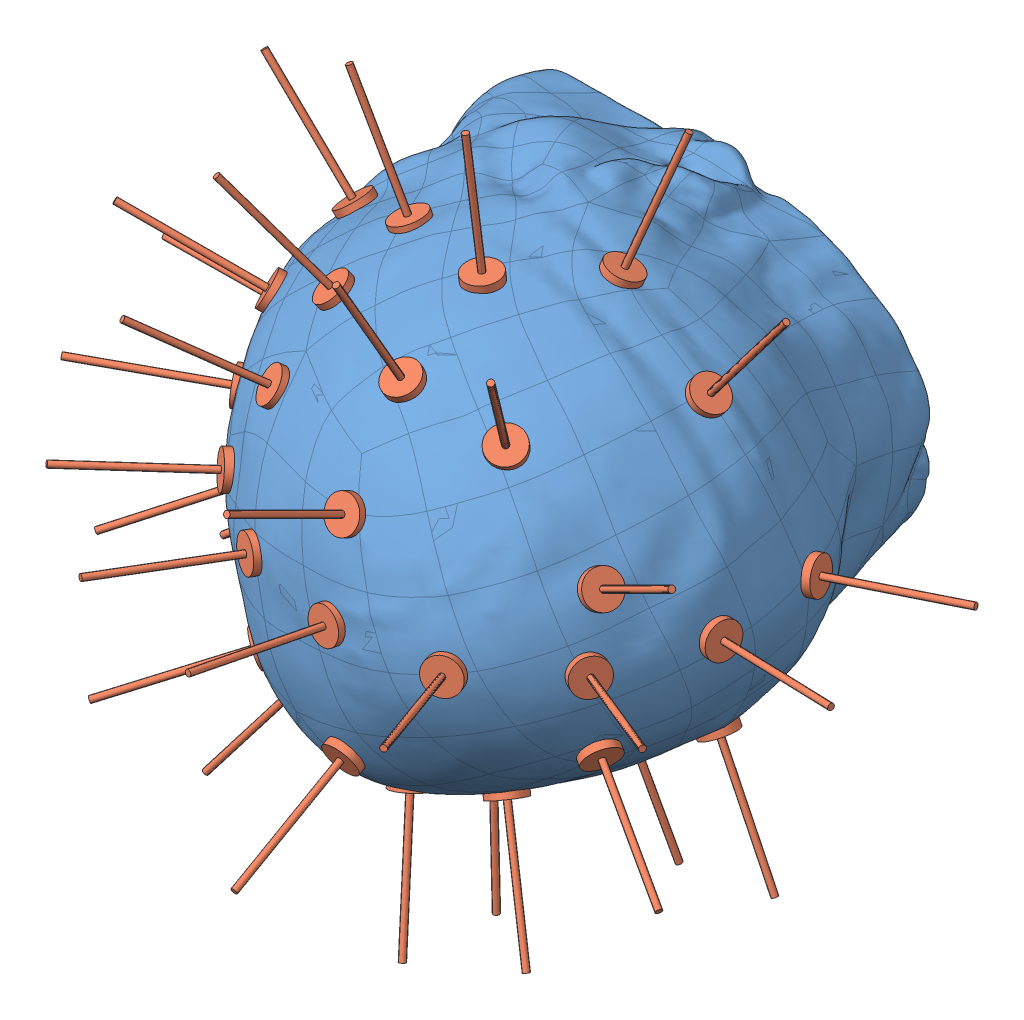
SolidWorks assembly 2_Electrode Positioning, configuration AgCL Elecs. Lengths in mm.
Overall size (190.88 167.77 151.53).
37 component instances, 4 part files, 135 mates.
Components (placement in the parent):
- 1_Creating_Electrode_Positions-1: 1_Creating_Electrode_Positions [Default] at origin
- 0_Electrode_with_clearance -1: 0_Electrode_with_clearance  [AgCL_Small_Elec] at (-101.3217 -81.8741 504.0543) x (0.599277 -0.793127 -0.108704) z (-0.754058 -0.604849 0.256036) size (38 8.5 8.5) (hidden)
- 0_Electrode_with_clearance -2: 0_Electrode_with_clearance  [AgCL_Small_Elec] at (-82.2889 -183.2344 567.2177) x (0.645389 0.335773 -0.686098) z (-0.469655 -0.533934 -0.703093) size (38 8.5 8.5) (hidden)
- 0_Electrode_with_clearance -3: 0_Electrode_with_clearance  [AgCL_Small_Elec] at (-21.5544 -182.7483 591.4589) x (-0.043069 0.440922 -0.896512) z (0.452439 -0.791448 -0.410985) size (38 8.5 8.5) (hidden)
- 0_Electrode_with_clearance -4: 0_Electrode_with_clearance  [AgCL_Small_Elec] at (-79.3288 -210.763 540.8916) x (0.521346 0.779713 -0.346765) z (0.847412 -0.520885 0.10282) size (38 8.5 8.5) (hidden)
- 0_Electrode_with_clearance -5: 0_Electrode_with_clearance  [AgCL_Small_Elec] at (-110.6313 -192.4083 505.1158) x (0.780765 0.610117 -0.134774) z (0.617331 -0.719934 0.317172) size (38 8.5 8.5) (hidden)
- 0_Electrode_with_clearance -6: 0_Electrode_with_clearance  [AgCL_Small_Elec] at (-109.077 -173.871 538.7683) x (0.685975 0.399364 -0.608232) z (0.52825 0.301522 0.793748) size (38 8.5 8.5) (hidden)
- 0_Electrode_with_clearance -7: 0_Electrode_with_clearance  [AgCL_Small_Elec] at (-62.0005 -135.1023 589.8279) x (0.414132 -0.080495 -0.906651) z (-0.0951 -0.994457 0.044852) size (38 8.5 8.5) (hidden)
- 0_Electrode_with_clearance -8: 0_Electrode_with_clearance  [AgCL_Small_Elec] at (-26.2629 -133.863 598.3827) x (0.096504 -0.11805 -0.988307) z (-0.044866 -0.992448 0.114163) size (38 8.5 8.5) (hidden)
- 0_Electrode_with_clearance -9: 0_Electrode_with_clearance  [AgCL_Small_Elec] at (16.3229 -132.4483 591.5644) x (-0.423671 -0.160919 -0.891408) z (0.905732 -0.061861 -0.419312) size (38 8.5 8.5) (hidden)
- 0_Electrode_with_clearance -10: 0_Electrode_with_clearance  [AgCL_Small_Elec] at (-76.3664 -218.9806 512.3458) x (0.403148 0.911153 -0.085279) z (-0.91288 0.393867 -0.107329) size (38 8.5 8.5) (hidden)
- 0_Electrode_with_clearance -11: 0_Electrode_with_clearance  [AgCL_Small_Elec] at (-16.7384 -214.7756 553.7465) x (-0.27015 0.904193 -0.330838) z (0.363231 -0.222513 -0.904738) size (38 8.5 8.5) (hidden)
- 0_Electrode_with_clearance -12: 0_Electrode_with_clearance  [AgCL_Small_Elec] at (9.9013 -206.0821 549.0584) x (-0.44413 0.847467 -0.290773) z (0.27601 -0.179341 -0.944275) size (38 8.5 8.5) (hidden)
- 0_Electrode_with_clearance -13: 0_Electrode_with_clearance  [AgCL_Small_Elec] at (-25.8693 -225.0397 520.8484) x (-0.108878 0.990756 -0.080919) z (0.326961 -0.041181 -0.94414) size (38 8.5 8.5) (hidden)
- 0_Electrode_with_clearance -14: 0_Electrode_with_clearance  [AgCL_Small_Elec] at (-9.153 -220.2716 491.3702) x (-0.275461 0.948005 0.159398) z (0.23104 0.22624 -0.946275) size (38 8.5 8.5) (hidden)
- 0_Electrode_with_clearance -15: 0_Electrode_with_clearance  [AgCL_Small_Elec] at (26.5261 -204.2268 502.863) x (-0.485851 0.873045 -0.041733) z (0.233099 0.083406 -0.96887) size (38 8.5 8.5) (hidden)
- 0_Electrode_with_clearance -16: 0_Electrode_with_clearance  [AgCL_Small_Elec] at (-25.2881 -103.033 589.5857) x (0.02345 -0.436886 -0.899211) z (0.616305 -0.701894 0.35709) size (38 8.5 8.5) (hidden)
- 0_Electrode_with_clearance -17: 0_Electrode_with_clearance  [AgCL_Small_Elec] at (49.4991 -132.0869 559.3095) x (-0.872293 -0.171869 -0.457783) z (0.368185 0.385224 -0.846193) size (38 8.5 8.5) (hidden)
- 0_Electrode_with_clearance -18: 0_Electrode_with_clearance  [AgCL_Small_Elec] at (44.1979 -106.1627 546.607) x (-0.806539 -0.531711 -0.258415) z (-0.500209 0.84676 -0.181078) size (38 8.5 8.5) (hidden)
- 0_Electrode_with_clearance -19: 0_Electrode_with_clearance  [AgCL_Small_Elec] at (45.6239 -173.6394 551.289) x (-0.805041 0.480174 -0.348342) z (0.061106 -0.51696 -0.853826) size (38 8.5 8.5) (hidden)
- 0_Electrode_with_clearance -20: 0_Electrode_with_clearance  [AgCL_Small_Elec] at (61.7604 -134.4581 523.9268) x (-0.986679 -0.100015 -0.1283) z (0.083334 -0.988087 0.129378) size (38 8.5 8.5) (hidden)
- 0_Electrode_with_clearance -21: 0_Electrode_with_clearance  [AgCL_Small_Elec] at (28.3608 -77.9895 501.8243) x (-0.605728 -0.795669 -0.002061) z (0.707034 -0.539436 0.457287) size (38 8.5 8.5) (hidden)
- 0_Electrode_with_clearance -22: 0_Electrode_with_clearance  [AgCL_Small_Elec] at (58.6439 -133.8669 484.1657) x (-0.948505 -0.117932 0.293989) z (0.315365 -0.264534 0.911354) size (38 8.5 8.5) (hidden)
- 0_Electrode_with_clearance -23: 0_Electrode_with_clearance  [AgCL_Small_Elec] at (-10.0826 -62.5213 487.9314) x (-0.251148 -0.931297 0.263838) z (0.611907 0.058442 0.788767) size (38 8.5 8.5) (hidden)
- 0_Electrode_with_clearance -24: 0_Electrode_with_clearance  [AgCL_Small_Elec] at (6.1438 -76.2016 554.3064) x (-0.334952 -0.825131 -0.454935) z (0.746461 -0.527012 0.406268) size (38 8.5 8.5) (hidden)
- 0_Electrode_with_clearance -25: 0_Electrode_with_clearance  [AgCL_Small_Elec] at (-75.1506 -96.9569 566.1233) x (0.501835 -0.539515 -0.676081) z (-0.533614 -0.808268 0.248915) size (38 8.5 8.5) (hidden)
- 0_Electrode_with_clearance -26: 0_Electrode_with_clearance  [AgCL_Small_Elec] at (-33.0522 -57.4526 521.5183) x (0.03497 -0.994627 -0.097441) z (0.11782 -0.092718 0.988697) size (38 8.5 8.5) (hidden)
- 0_Electrode_with_clearance -27: 0_Electrode_with_clearance  [AgCL_Small_Elec] at (-28.7224 -70.1153 558.5267) x (0.027631 -0.870337 -0.491681) z (0.32043 -0.458202 0.829081) size (38 8.5 8.5) (hidden)
- 0_Electrode_with_clearance -28: 0_Electrode_with_clearance  [AgCL_Small_Elec] at (-73.8912 -76.1791 543.5939) x (0.463089 -0.762821 -0.45128) z (0.644267 -0.059941 0.762448) size (38 8.5 8.5) (hidden)
- 0_Electrode_with_clearance -29: 0_Electrode_with_clearance  [AgCL_Small_Elec] at (-71.0435 -65.5829 512.8984) x (0.360614 -0.926276 -0.109405) z (-0.8908 -0.307263 -0.334762) size (38 8.5 8.5) (hidden)
- 0_Electrode_with_clearance -30: 0_Electrode_with_clearance  [AgCL_Small_Elec] at (-128.9888 -138.0006 501.461) x (0.999967 0.007333 -0.00359) z (0.007908 -0.979244 0.202533) size (38 8.5 8.5) (hidden)
- 0_Electrode_with_clearance -31: 0_Electrode_with_clearance  [AgCL_Small_Elec] at (-113.3952 -135.5851 543.1512) x (0.829987 -0.065864 -0.553881) z (-0.514032 0.295195 -0.805376) size (38 8.5 8.5) (hidden)
- 0_Electrode_with_clearance -32: 0_Electrode_with_clearance  [AgCL_Small_Elec] at (-109.5416 -104.4105 533.6089) x (0.764902 -0.453957 -0.456999) z (-0.44793 -0.8847 0.129089) size (38 8.5 8.5) (hidden)
- 0_Electrode_with_clearance -33: 0_Electrode_with_clearance  [AgCL_Small_Elec] at (-89.9639 -133.928 570.4218) x (0.620398 -0.11608 -0.775649) z (-0.284363 -0.954983 -0.084527) size (38 8.5 8.5) (hidden)
- 1_Creating_Electrode_Positions-2: 1_Creating_Electrode_Positions [Default] at origin
- All_Electrodes_Positioned-1: All_Electrodes_Positioned [Default] at origin (suppressed, hidden)
- All_AgCl_Positioned-1: All_AgCl_Positioned [Default] at origin size (190.88 167.77 115.05)
Mates (geometry in assembly coordinates):
- Concentric1: concentric anti-aligned: line of 1_Creating_Electrode_Positions-1 through (-81.5455 -108.0473 500.467) axis (-0.599277 0.793127 0.108704); cylinder of 0_Electrode_with_clearance -1 through (-81.5455 -108.0473 500.467) axis (0.599277 -0.793127 -0.108704) radius 2.1
- Distance1: distance = 5 mm: plane of 0_Electrode_with_clearance -1 through (-78.5491 -112.0129 499.9235) normal (0.599277 -0.793127 -0.108704); point of 1_Creating_Electrode_Positions-1
- Concentric2: concentric anti-aligned: line of 1_Creating_Electrode_Positions-1 through (-86.4398 -160.692 518.6967) axis (-0.685975 -0.399364 0.608232); cylinder of 0_Electrode_with_clearance -6 through (-86.4398 -160.692 518.6967) axis (0.685975 0.399364 -0.608232) radius 2.1
- Distance2: distance = 5 mm: plane of 0_Electrode_with_clearance -6 through (-83.0099 -158.6952 515.6555) normal (0.685975 0.399364 -0.608232); point of 1_Creating_Electrode_Positions-1
- Concentric3: concentric anti-aligned: line of 1_Creating_Electrode_Positions-1 through (-84.8661 -172.2744 500.6683) axis (-0.780765 -0.610117 0.134774); cylinder of 0_Electrode_with_clearance -5 through (-84.8661 -172.2744 500.6683) axis (0.780765 0.610117 -0.134774) radius 2.1
- Distance3: distance = 5 mm: plane of 0_Electrode_with_clearance -5 through (-80.9623 -169.2238 499.9944) normal (0.780765 0.610117 -0.134774); point of 1_Creating_Electrode_Positions-1
- Concentric5: concentric anti-aligned: line of 1_Creating_Electrode_Positions-1 through (-58.0591 -178.9526 526.7445) axis (-0.521346 -0.779713 0.346765); cylinder of 0_Electrode_with_clearance -4 through (-62.1243 -185.0325 529.4484) axis (0.521346 0.779713 -0.346765) radius 2.1
- Distance4: distance = 5 mm: plane of 0_Electrode_with_clearance -4 through (-59.5176 -181.134 527.7146) normal (0.521346 0.779713 -0.346765); point of 1_Creating_Electrode_Positions-1
- Concentric8: concentric anti-aligned: line of 1_Creating_Electrode_Positions-1 through (-60.9911 -172.1539 544.5765) axis (-0.645389 -0.335773 0.686098); cylinder of 0_Electrode_with_clearance -2 through (-60.9911 -172.1539 544.5765) axis (0.645389 0.335773 -0.686098) radius 2.1
- Distance5: distance = 5 mm: plane of 0_Electrode_with_clearance -2 through (-57.7642 -170.4751 541.146) normal (0.645389 0.335773 -0.686098); point of 1_Creating_Electrode_Positions-1
- Concentric9: concentric anti-aligned: line of 1_Creating_Electrode_Positions-1 through (-22.9757 -168.1979 561.874) axis (0.043069 -0.440922 0.896512); cylinder of 0_Electrode_with_clearance -3 through (-22.9757 -168.1979 561.874) axis (-0.043069 0.440922 -0.896512) radius 2.1
- Distance6: distance = 5 mm: point of 1_Creating_Electrode_Positions-1; plane of 0_Electrode_with_clearance -3 through (-23.191 -165.9933 557.3915) normal (-0.043069 0.440922 -0.896512)
- Concentric10: concentric anti-aligned: line of 1_Creating_Electrode_Positions-1 through (-48.3342 -137.7586 559.9084) axis (-0.414132 0.080495 0.906651); cylinder of 0_Electrode_with_clearance -7 through (-48.3342 -137.7586 559.9084) axis (0.414132 -0.080495 -0.906651) radius 2.1
- Distance7: distance = 5 mm: plane of 0_Electrode_with_clearance -7 through (-46.2635 -138.1611 555.3751) normal (0.414132 -0.080495 -0.906651); point of 1_Creating_Electrode_Positions-1
- Concentric11: concentric anti-aligned: line of 1_Creating_Electrode_Positions-1 through (-23.0782 -137.7586 565.7686) axis (-0.096504 0.11805 0.988307); cylinder of 0_Electrode_with_clearance -8 through (-23.0782 -137.7586 565.7686) axis (0.096504 -0.11805 -0.988307) radius 2.1
- Distance8: distance = 5 mm: plane of 0_Electrode_with_clearance -8 through (-22.5957 -138.3489 560.827) normal (0.096504 -0.11805 -0.988307); point of 1_Creating_Electrode_Positions-1
- Concentric12: concentric anti-aligned: line of 1_Creating_Electrode_Positions-1 through (-1.7771 -139.323 553.4819) axis (0.423671 0.160919 0.891408); cylinder of 0_Electrode_with_clearance -9 through (2.3417 -137.7586 562.148) axis (-0.423671 -0.160919 -0.891408) radius 2.1
- Distance9: distance = 5 mm: plane of 0_Electrode_with_clearance -9 through (0.2234 -138.5632 557.6909) normal (-0.423671 -0.160919 -0.891408); point of 1_Creating_Electrode_Positions-1
- Concentric13: concentric anti-aligned: line of 1_Creating_Electrode_Positions-1 through (-59.4862 -180.8298 508.7751) axis (-0.403148 -0.911153 0.085279); cylinder of 0_Electrode_with_clearance -10 through (-63.0625 -188.9125 509.5316) axis (0.403148 0.911153 -0.085279) radius 2.1
- Distance10: distance = 5 mm: point of 1_Creating_Electrode_Positions-1; plane of 0_Electrode_with_clearance -10 through (-61.0468 -184.3568 509.1052) normal (0.403148 0.911153 -0.085279)
- Concentric14: concentric anti-aligned: line of 1_Creating_Electrode_Positions-1 through (-28.1573 -176.5567 539.7624) axis (0.27015 -0.904193 0.330838); cylinder of 0_Electrode_with_clearance -11 through (-25.6534 -184.9372 542.8288) axis (-0.27015 0.904193 -0.330838) radius 2.1
- Distance11: distance = 5 mm: point of 1_Creating_Electrode_Positions-1; plane of 0_Electrode_with_clearance -11 through (-27.0041 -180.4163 541.1746) normal (-0.27015 0.904193 -0.330838)
- Concentric15: concentric anti-aligned: line of 1_Creating_Electrode_Positions-1 through (-4.755 -178.1157 539.4629) axis (0.44413 -0.847467 0.290773); cylinder of 0_Electrode_with_clearance -12 through (-4.755 -178.1157 539.4629) axis (-0.44413 0.847467 -0.290773) radius 2.1
- Distance12: distance = 5 mm: point of 1_Creating_Electrode_Positions-1; plane of 0_Electrode_with_clearance -12 through (-6.9757 -173.8784 538.0091) normal (-0.44413 0.847467 -0.290773)
- Concentric16: concentric anti-aligned: line of 1_Creating_Electrode_Positions-1 through (-29.4623 -192.3447 518.1781) axis (0.108878 -0.990756 0.080919); cylinder of 0_Electrode_with_clearance -13 through (-29.4623 -192.3447 518.1781) axis (-0.108878 0.990756 -0.080919) radius 2.1
- Distance13: distance = 5 mm: point of 1_Creating_Electrode_Positions-1; plane of 0_Electrode_with_clearance -13 through (-30.0067 -187.3909 517.7735) normal (-0.108878 0.990756 -0.080919)
- Concentric17: concentric anti-aligned: line of 1_Creating_Electrode_Positions-1 through (-20.4193 -181.4984 497.8895) axis (0.275461 -0.948005 -0.159398); cylinder of 0_Electrode_with_clearance -14 through (-18.2432 -188.9874 496.6303) axis (-0.275461 0.948005 0.159398) radius 2.1
- Distance14: distance = 5 mm: point of 1_Creating_Electrode_Positions-1; plane of 0_Electrode_with_clearance -14 through (-19.6205 -184.2474 497.4273) normal (-0.275461 0.948005 0.159398)
- Concentric18: concentric anti-aligned: line of 1_Creating_Electrode_Positions-1 through (10.4931 -175.4164 501.4858) axis (0.485851 -0.873045 0.041733); cylinder of 0_Electrode_with_clearance -15 through (10.4931 -175.4164 501.4858) axis (-0.485851 0.873045 -0.041733) radius 2.1
- Distance15: distance = 5 mm: point of 1_Creating_Electrode_Positions-1; plane of 0_Electrode_with_clearance -15 through (8.0638 -171.0511 501.2771) normal (-0.485851 0.873045 -0.041733)
- Concentric19: concentric anti-aligned: line of 1_Creating_Electrode_Positions-1 through (14.1338 -154.8568 537.6632) axis (0.805041 -0.480174 0.348342); cylinder of 0_Electrode_with_clearance -19 through (19.0575 -157.7936 539.7937) axis (-0.805041 0.480174 -0.348342) radius 2.1
- Distance16: distance = 5 mm: point of 1_Creating_Electrode_Positions-1; plane of 0_Electrode_with_clearance -19 through (15.0323 -155.3928 538.052) normal (-0.805041 0.480174 -0.348342)
- Concentric20: concentric anti-aligned: line of 1_Creating_Electrode_Positions-1 through (20.7135 -137.7586 544.2026) axis (0.872293 0.171869 0.457783); cylinder of 0_Electrode_with_clearance -17 through (20.7135 -137.7586 544.2026) axis (-0.872293 -0.171869 -0.457783) radius 2.1
- Distance17: distance = 5 mm: plane of 0_Electrode_with_clearance -17 through (16.352 -138.618 541.9137) normal (-0.872293 -0.171869 -0.457783); point of 1_Creating_Electrode_Positions-1
- Concentric21: concentric anti-aligned: line of 1_Creating_Electrode_Positions-1 through (-24.5142 -117.4502 559.9117) axis (-0.02345 0.436886 0.899211); cylinder of 0_Electrode_with_clearance -16 through (-24.5142 -117.4502 559.9117) axis (0.02345 -0.436886 -0.899211) radius 2.1
- Distance18: distance = 5 mm: point of 1_Creating_Electrode_Positions-1; plane of 0_Electrode_with_clearance -16 through (-24.397 -119.6346 555.4157) normal (0.02345 -0.436886 -0.899211)
- Concentric23: concentric anti-aligned: line of 1_Creating_Electrode_Positions-1 through (10.7527 -128.2114 535.8912) axis (0.806539 0.531711 0.258415); cylinder of 0_Electrode_with_clearance -18 through (17.5821 -123.7092 538.0793) axis (-0.806539 -0.531711 -0.258415) radius 2.1
- Distance19: distance = 5 mm: point of 1_Creating_Electrode_Positions-1; plane of 0_Electrode_with_clearance -18 through (13.5494 -126.3677 536.7872) normal (-0.806539 -0.531711 -0.258415)
- Concentric24: concentric anti-aligned: line of 1_Creating_Electrode_Positions-1 through (20.8846 -138.6015 518.6116) axis (0.986679 0.100015 0.1283); cylinder of 0_Electrode_with_clearance -20 through (29.2 -137.7586 519.6929) axis (-0.986679 -0.100015 -0.1283) radius 2.1
- Distance20: distance = 5 mm: plane of 0_Electrode_with_clearance -20 through (24.2666 -138.2587 519.0514) normal (-0.986679 -0.100015 -0.1283); point of 1_Creating_Electrode_Positions-1
- Concentric25: concentric anti-aligned: line of 1_Creating_Electrode_Positions-1 through (8.3718 -104.2466 501.7563) axis (0.605728 0.795669 0.002061); cylinder of 0_Electrode_with_clearance -21 through (8.3718 -104.2466 501.7563) axis (-0.605728 -0.795669 -0.002061) radius 2.1
- Distance21: distance = 5 mm: point of 1_Creating_Electrode_Positions-1; plane of 0_Electrode_with_clearance -21
- Concentric26: concentric anti-aligned: line of 1_Creating_Electrode_Positions-1 through (27.3432 -137.7586 493.8674) axis (0.948505 0.117932 -0.293989); cylinder of 0_Electrode_with_clearance -22 through (27.3432 -137.7586 493.8674) axis (-0.948505 -0.117932 0.293989) radius 2.1
- Distance22: distance = 5 mm: plane of 0_Electrode_with_clearance -22 through (22.6007 -138.3483 495.3373) normal (-0.948505 -0.117932 0.293989); point of 1_Creating_Electrode_Positions-1
- Concentric27: concentric anti-aligned: line of 1_Creating_Electrode_Positions-1 through (-18.3704 -93.2541 496.638) axis (0.251148 0.931297 -0.263838); cylinder of 0_Electrode_with_clearance -23 through (-18.3704 -93.2541 496.638) axis (-0.251148 -0.931297 0.263838) radius 2.1
- Distance23: distance = 5 mm: plane of 0_Electrode_with_clearance -23 through (-19.6262 -97.9106 497.9572) normal (-0.251148 -0.931297 0.263838); point of 1_Creating_Electrode_Positions-1
- Concentric28: concentric anti-aligned: line of 1_Creating_Electrode_Positions-1 through (-4.9096 -103.431 539.2935) axis (0.334952 0.825131 0.454935); cylinder of 0_Electrode_with_clearance -24 through (-4.9096 -103.431 539.2935) axis (-0.334952 -0.825131 -0.454935) radius 2.1
- Distance24: distance = 5 mm: point of 1_Creating_Electrode_Positions-1; plane of 0_Electrode_with_clearance -24 through (-6.5844 -107.5566 537.0189) normal (-0.334952 -0.825131 -0.454935)
- Concentric29: concentric anti-aligned: line of 1_Creating_Electrode_Positions-1 through (-27.5526 -106.9607 537.7116) axis (-0.027631 0.870337 0.491681); cylinder of 0_Electrode_with_clearance -27 through (-27.8105 -98.8364 542.3012) axis (0.027631 -0.870337 -0.491681) radius 2.1
- Distance25: distance = 5 mm: point of 1_Creating_Electrode_Positions-1; plane of 0_Electrode_with_clearance -27 through (-27.6724 -103.1881 539.8428) normal (0.027631 -0.870337 -0.491681)
- Concentric30: concentric anti-aligned: line of 1_Creating_Electrode_Positions-1 through (-53.6573 -120.064 537.1671) axis (-0.501835 0.539515 0.676081); cylinder of 0_Electrode_with_clearance -25 through (-58.5901 -114.7609 543.8127) axis (0.501835 -0.539515 -0.676081) radius 2.1
- Distance26: distance = 5 mm: plane of 0_Electrode_with_clearance -25 through (-56.0809 -117.4585 540.4322) normal (0.501835 -0.539515 -0.676081); point of 1_Creating_Electrode_Positions-1
- Concentric32: concentric anti-aligned: line of 1_Creating_Electrode_Positions-1 through (-59.1432 -96.1501 509.288) axis (-0.360614 0.926276 0.109405); cylinder of 0_Electrode_with_clearance -29 through (-59.1432 -96.1501 509.288) axis (0.360614 -0.926276 -0.109405) radius 2.1
- Distance27: distance = 5 mm: plane of 0_Electrode_with_clearance -29 through (-57.3402 -100.7814 508.741) normal (0.360614 -0.926276 -0.109405); point of 1_Creating_Electrode_Positions-1
- Concentric33: concentric anti-aligned: line of 1_Creating_Electrode_Positions-1 through (-58.6093 -101.3522 528.7016) axis (-0.463089 0.762821 0.45128); cylinder of 0_Electrode_with_clearance -28 through (-58.6093 -101.3522 528.7016) axis (0.463089 -0.762821 -0.45128) radius 2.1
- Distance28: distance = 5 mm: point of 1_Creating_Electrode_Positions-1; plane of 0_Electrode_with_clearance -28 through (-56.2938 -105.1663 526.4452) normal (0.463089 -0.762821 -0.45128)
- Concentric34: concentric anti-aligned: line of 1_Creating_Electrode_Positions-1 through (-31.8982 -90.2753 518.3028) axis (-0.03497 0.994627 0.097441); cylinder of 0_Electrode_with_clearance -26 through (-31.8982 -90.2753 518.3028) axis (0.03497 -0.994627 -0.097441) radius 2.1
- Distance29: distance = 5 mm: point of 1_Creating_Electrode_Positions-1; plane of 0_Electrode_with_clearance -26 through (-31.7233 -95.2484 517.8155) normal (0.03497 -0.994627 -0.097441)
- Concentric35: concentric anti-aligned: line of 1_Creating_Electrode_Positions-1 through (-95.9899 -137.7586 501.3425) axis (-0.999967 -0.007333 0.00359); cylinder of 0_Electrode_with_clearance -30 through (-95.9899 -137.7586 501.3425) axis (0.999967 0.007333 -0.00359) radius 2.1
- Distance30: distance = 5 mm: point of 1_Creating_Electrode_Positions-1; plane of 0_Electrode_with_clearance -30 through (-90.9901 -137.722 501.3245) normal (0.999967 0.007333 -0.00359)
- Concentric36: concentric anti-aligned: line of 1_Creating_Electrode_Positions-1 through (-86.0056 -137.7586 524.8731) axis (-0.829987 0.065864 0.553881); cylinder of 0_Electrode_with_clearance -31 through (-86.0056 -137.7586 524.8731) axis (0.829987 -0.065864 -0.553881) radius 2.1
- Distance31: distance = 5 mm: point of 1_Creating_Electrode_Positions-1; plane of 0_Electrode_with_clearance -31 through (-81.8557 -138.088 522.1037) normal (0.829987 -0.065864 -0.553881)
- Concentric37: concentric anti-aligned: line of 1_Creating_Electrode_Positions-1 through (-84.2998 -119.3911 518.528) axis (-0.764902 0.453957 0.456999); cylinder of 0_Electrode_with_clearance -32 through (-84.2998 -119.3911 518.528) axis (0.764902 -0.453957 -0.456999) radius 2.1
- Distance32: distance = 5 mm: point of 1_Creating_Electrode_Positions-1; plane of 0_Electrode_with_clearance -32 through (-80.4753 -121.6609 516.243) normal (0.764902 -0.453957 -0.456999)
- Concentric38: concentric anti-aligned: line of 1_Creating_Electrode_Positions-1 through (-69.4908 -137.7586 544.8254) axis (-0.620398 0.11608 0.775649); cylinder of 0_Electrode_with_clearance -33 through (-69.4908 -137.7586 544.8254) axis (0.620398 -0.11608 -0.775649) radius 2.1
- Distance33: distance = 5 mm: point of 1_Creating_Electrode_Positions-1; plane of 0_Electrode_with_clearance -33 through (-66.3888 -138.339 540.9471) normal (0.620398 -0.11608 -0.775649)
- Coincident40: coincident aligned: plane of 1_Creating_Electrode_Positions-1; plane of 1_Creating_Electrode_Positions-2
- Coincident41: coincident aligned: plane of 1_Creating_Electrode_Positions-1 through (0 0 0) normal (0 1 0); plane of 1_Creating_Electrode_Positions-2 through (0 0 0) normal (0 1 0)
- Coincident42: coincident aligned: plane of 1_Creating_Electrode_Positions-1 through (0 0 0) normal (1 0 0); plane of 1_Creating_Electrode_Positions-2 through (0 0 0) normal (1 0 0)
- Coincident43: coincident anti-aligned: line of 1_Creating_Electrode_Positions-1 through (-60.9911 -172.1539 544.5765) axis (-0.645389 -0.335773 0.686098); line of 0_Electrode_with_clearance -2 through (-82.2889 -183.2344 567.2177) axis (0.645389 0.335773 -0.686098)
- Coincident44: coincident: point of 1_Creating_Electrode_Positions-1; point of 0_Electrode_with_clearance -2
- Coincident45: coincident anti-aligned: line of 1_Creating_Electrode_Positions-1 through (-81.5455 -108.0473 500.467) axis (-0.599277 0.793127 0.108704); line of 0_Electrode_with_clearance -1 through (-101.3217 -81.8741 504.0543) axis (0.599277 -0.793127 -0.108704)
- Coincident46: coincident: point of 1_Creating_Electrode_Positions-1; point of 0_Electrode_with_clearance -1
- Coincident47: coincident anti-aligned: line of 1_Creating_Electrode_Positions-1 through (-22.9757 -168.1979 561.874) axis (0.043069 -0.440922 0.896512); line of 0_Electrode_with_clearance -3 through (-21.5544 -182.7483 591.4589) axis (-0.043069 0.440922 -0.896512)
- Coincident48: coincident: point of 1_Creating_Electrode_Positions-1; point of 0_Electrode_with_clearance -3
- Coincident49: coincident anti-aligned: line of 1_Creating_Electrode_Positions-1 through (-58.0591 -178.9526 526.7445) axis (-0.521346 -0.779713 0.346765); line of 0_Electrode_with_clearance -4 through (-79.3288 -210.763 540.8916) axis (0.521346 0.779713 -0.346765)
- Coincident50: coincident: point of 1_Creating_Electrode_Positions-1; point of 0_Electrode_with_clearance -4
- Coincident51: coincident anti-aligned: line of 1_Creating_Electrode_Positions-1 through (-84.8661 -172.2744 500.6683) axis (-0.780765 -0.610117 0.134774); line of 0_Electrode_with_clearance -5 through (-110.6313 -192.4083 505.1158) axis (0.780765 0.610117 -0.134774)
- Coincident52: coincident: point of 1_Creating_Electrode_Positions-1; point of 0_Electrode_with_clearance -5
- Coincident53: coincident anti-aligned: line of 1_Creating_Electrode_Positions-1 through (-86.4398 -160.692 518.6967) axis (-0.685975 -0.399364 0.608232); line of 0_Electrode_with_clearance -6 through (-109.077 -173.871 538.7683) axis (0.685975 0.399364 -0.608232)
- Coincident54: coincident: point of 1_Creating_Electrode_Positions-1; point of 0_Electrode_with_clearance -6
- Coincident55: coincident anti-aligned: line of 1_Creating_Electrode_Positions-1 through (-48.3342 -137.7586 559.9084) axis (-0.414132 0.080495 0.906651); line of 0_Electrode_with_clearance -7 through (-62.0005 -135.1023 589.8279) axis (0.414132 -0.080495 -0.906651)
- Coincident56: coincident: point of 1_Creating_Electrode_Positions-1; point of 0_Electrode_with_clearance -7
- Coincident57: coincident anti-aligned: line of 1_Creating_Electrode_Positions-1 through (-23.0782 -137.7586 565.7686) axis (-0.096504 0.11805 0.988307); line of 0_Electrode_with_clearance -8 through (-26.2629 -133.863 598.3827) axis (0.096504 -0.11805 -0.988307)
- Coincident58: coincident: point of 1_Creating_Electrode_Positions-1; point of 0_Electrode_with_clearance -8
- Coincident59: coincident anti-aligned: line of 1_Creating_Electrode_Positions-1 through (-1.7771 -139.323 553.4819) axis (0.423671 0.160919 0.891408); line of 0_Electrode_with_clearance -9 through (16.3229 -132.4483 591.5644) axis (-0.423671 -0.160919 -0.891408)
- Coincident60: coincident: point of 1_Creating_Electrode_Positions-1; point of 0_Electrode_with_clearance -9
- Coincident61: coincident anti-aligned: line of 1_Creating_Electrode_Positions-1 through (-59.4862 -180.8298 508.7751) axis (-0.403148 -0.911153 0.085279); line of 0_Electrode_with_clearance -10 through (-76.3664 -218.9806 512.3458) axis (0.403148 0.911153 -0.085279)
- Coincident62: coincident: point of 1_Creating_Electrode_Positions-1; point of 0_Electrode_with_clearance -10
- Coincident63: coincident anti-aligned: line of 1_Creating_Electrode_Positions-1 through (-28.1573 -176.5567 539.7624) axis (0.27015 -0.904193 0.330838); line of 0_Electrode_with_clearance -11 through (-16.7384 -214.7756 553.7465) axis (-0.27015 0.904193 -0.330838)
- Coincident64: coincident: point of 1_Creating_Electrode_Positions-1; point of 0_Electrode_with_clearance -11
- Coincident65: coincident anti-aligned: line of 1_Creating_Electrode_Positions-1 through (-4.755 -178.1157 539.4629) axis (0.44413 -0.847467 0.290773); line of 0_Electrode_with_clearance -12 through (9.9013 -206.0821 549.0584) axis (-0.44413 0.847467 -0.290773)
- Coincident66: coincident: point of 1_Creating_Electrode_Positions-1; point of 0_Electrode_with_clearance -12
- Coincident67: coincident anti-aligned: line of 1_Creating_Electrode_Positions-1 through (-29.4623 -192.3447 518.1781) axis (0.108878 -0.990756 0.080919); line of 0_Electrode_with_clearance -13 through (-25.8693 -225.0397 520.8484) axis (-0.108878 0.990756 -0.080919)
- Coincident68: coincident: point of 1_Creating_Electrode_Positions-1; point of 0_Electrode_with_clearance -13
- Coincident69: coincident anti-aligned: line of 1_Creating_Electrode_Positions-1 through (-20.4193 -181.4984 497.8895) axis (0.275461 -0.948005 -0.159398); line of 0_Electrode_with_clearance -14 through (-9.153 -220.2716 491.3702) axis (-0.275461 0.948005 0.159398)
- Coincident70: coincident: point of 1_Creating_Electrode_Positions-1; point of 0_Electrode_with_clearance -14
- Coincident71: coincident anti-aligned: line of 1_Creating_Electrode_Positions-1 through (10.4931 -175.4164 501.4858) axis (0.485851 -0.873045 0.041733); line of 0_Electrode_with_clearance -15 through (26.5261 -204.2268 502.863) axis (-0.485851 0.873045 -0.041733)
- Coincident72: coincident: point of 1_Creating_Electrode_Positions-1; point of 0_Electrode_with_clearance -15
- Coincident73: coincident anti-aligned: line of 1_Creating_Electrode_Positions-1 through (-24.5142 -117.4502 559.9117) axis (-0.02345 0.436886 0.899211); line of 0_Electrode_with_clearance -16 through (-25.2881 -103.033 589.5857) axis (0.02345 -0.436886 -0.899211)
- Coincident74: coincident: point of 1_Creating_Electrode_Positions-1; point of 0_Electrode_with_clearance -16
- Coincident75: coincident anti-aligned: line of 1_Creating_Electrode_Positions-1 through (20.7135 -137.7586 544.2026) axis (0.872293 0.171869 0.457783); line of 0_Electrode_with_clearance -17 through (49.4991 -132.0869 559.3095) axis (-0.872293 -0.171869 -0.457783)
- Coincident76: coincident: point of 1_Creating_Electrode_Positions-1; point of 0_Electrode_with_clearance -17
- Coincident77: coincident: point of 1_Creating_Electrode_Positions-1; point of 0_Electrode_with_clearance -18
- Coincident78: coincident anti-aligned: line of 1_Creating_Electrode_Positions-1 through (10.7527 -128.2114 535.8912) axis (0.806539 0.531711 0.258415); line of 0_Electrode_with_clearance -18 through (44.1979 -106.1627 546.607) axis (-0.806539 -0.531711 -0.258415)
- Coincident79: coincident anti-aligned: line of 1_Creating_Electrode_Positions-1 through (14.1338 -154.8568 537.6632) axis (0.805041 -0.480174 0.348342); line of 0_Electrode_with_clearance -19 through (45.6239 -173.6394 551.289) axis (-0.805041 0.480174 -0.348342)
- Coincident80: coincident: point of 0_Electrode_with_clearance -19; point of 1_Creating_Electrode_Positions-1
- Coincident81: coincident anti-aligned: line of 1_Creating_Electrode_Positions-1 through (20.8846 -138.6015 518.6116) axis (0.986679 0.100015 0.1283); line of 0_Electrode_with_clearance -20 through (61.7604 -134.4581 523.9268) axis (-0.986679 -0.100015 -0.1283)
- Coincident82: coincident: point of 1_Creating_Electrode_Positions-1; point of 0_Electrode_with_clearance -20
- Coincident83: coincident: point of 0_Electrode_with_clearance -21; point of 1_Creating_Electrode_Positions-1
- Coincident84: coincident anti-aligned: line of 1_Creating_Electrode_Positions-1 through (8.3718 -104.2466 501.7563) axis (0.605728 0.795669 0.002061); line of 0_Electrode_with_clearance -21 through (28.3608 -77.9895 501.8243) axis (-0.605728 -0.795669 -0.002061)
- Coincident85: coincident: point of 1_Creating_Electrode_Positions-1; point of 0_Electrode_with_clearance -22
- Coincident86: coincident anti-aligned: line of 1_Creating_Electrode_Positions-1 through (27.3432 -137.7586 493.8674) axis (0.948505 0.117932 -0.293989); line of 0_Electrode_with_clearance -22 through (58.6439 -133.8669 484.1657) axis (-0.948505 -0.117932 0.293989)
- Coincident87: coincident: point of 1_Creating_Electrode_Positions-1; point of 0_Electrode_with_clearance -23
- Coincident88: coincident anti-aligned: line of 1_Creating_Electrode_Positions-1 through (-18.3704 -93.2541 496.638) axis (0.251148 0.931297 -0.263838); line of 0_Electrode_with_clearance -23 through (-10.0826 -62.5213 487.9314) axis (-0.251148 -0.931297 0.263838)
- Coincident89: coincident anti-aligned: line of 1_Creating_Electrode_Positions-1 through (-4.9096 -103.431 539.2935) axis (0.334952 0.825131 0.454935); line of 0_Electrode_with_clearance -24 through (6.1438 -76.2016 554.3064) axis (-0.334952 -0.825131 -0.454935)
- Coincident90: coincident: point of 1_Creating_Electrode_Positions-1; point of 0_Electrode_with_clearance -24
- Coincident91: coincident anti-aligned: line of 1_Creating_Electrode_Positions-1 through (-53.6573 -120.064 537.1671) axis (-0.501835 0.539515 0.676081); line of 0_Electrode_with_clearance -25 through (-75.1506 -96.9569 566.1233) axis (0.501835 -0.539515 -0.676081)
- Coincident92: coincident: point of 1_Creating_Electrode_Positions-1; point of 0_Electrode_with_clearance -25
- Coincident93: coincident anti-aligned: line of 1_Creating_Electrode_Positions-1 through (-31.8982 -90.2753 518.3028) axis (-0.03497 0.994627 0.097441); line of 0_Electrode_with_clearance -26 through (-33.0522 -57.4526 521.5183) axis (0.03497 -0.994627 -0.097441)
- Coincident94: coincident: point of 1_Creating_Electrode_Positions-1; point of 0_Electrode_with_clearance -26
- Coincident95: coincident anti-aligned: line of 1_Creating_Electrode_Positions-1 through (-27.5526 -106.9607 537.7116) axis (-0.027631 0.870337 0.491681); line of 0_Electrode_with_clearance -27 through (-28.7224 -70.1153 558.5267) axis (0.027631 -0.870337 -0.491681)
- Coincident96: coincident: point of 1_Creating_Electrode_Positions-1; point of 0_Electrode_with_clearance -27
- Coincident97: coincident anti-aligned: line of 1_Creating_Electrode_Positions-1 through (-58.6093 -101.3522 528.7016) axis (-0.463089 0.762821 0.45128); line of 0_Electrode_with_clearance -28 through (-73.8912 -76.1791 543.5939) axis (0.463089 -0.762821 -0.45128)
- Coincident98: coincident: point of 1_Creating_Electrode_Positions-1; point of 0_Electrode_with_clearance -28
- Coincident99: coincident anti-aligned: line of 1_Creating_Electrode_Positions-1 through (-59.1432 -96.1501 509.288) axis (-0.360614 0.926276 0.109405); line of 0_Electrode_with_clearance -29 through (-71.0435 -65.5829 512.8984) axis (0.360614 -0.926276 -0.109405)
- Coincident100: coincident: point of 1_Creating_Electrode_Positions-1; point of 0_Electrode_with_clearance -29
- Coincident101: coincident anti-aligned: line of 1_Creating_Electrode_Positions-1 through (-95.9899 -137.7586 501.3425) axis (-0.999967 -0.007333 0.00359); line of 0_Electrode_with_clearance -30 through (-128.9888 -138.0006 501.461) axis (0.999967 0.007333 -0.00359)
- Coincident102: coincident: point of 1_Creating_Electrode_Positions-1; point of 0_Electrode_with_clearance -30
- Coincident103: coincident anti-aligned: line of 1_Creating_Electrode_Positions-1 through (-86.0056 -137.7586 524.8731) axis (-0.829987 0.065864 0.553881); line of 0_Electrode_with_clearance -31 through (-113.3952 -135.5851 543.1512) axis (0.829987 -0.065864 -0.553881)
- Coincident104: coincident: point of 1_Creating_Electrode_Positions-1; point of 0_Electrode_with_clearance -31
- Coincident105: coincident anti-aligned: line of 1_Creating_Electrode_Positions-1 through (-84.2998 -119.3911 518.528) axis (-0.764902 0.453957 0.456999); line of 0_Electrode_with_clearance -32 through (-109.5416 -104.4105 533.6089) axis (0.764902 -0.453957 -0.456999)
- Coincident106: coincident: point of 1_Creating_Electrode_Positions-1; point of 0_Electrode_with_clearance -32
- Coincident107: coincident anti-aligned: line of 1_Creating_Electrode_Positions-1 through (-69.4908 -137.7586 544.8254) axis (-0.620398 0.11608 0.775649); line of 0_Electrode_with_clearance -33 through (-89.9639 -133.928 570.4218) axis (0.620398 -0.11608 -0.775649)
- Coincident108: coincident: point of 1_Creating_Electrode_Positions-1; point of 0_Electrode_with_clearance -33
